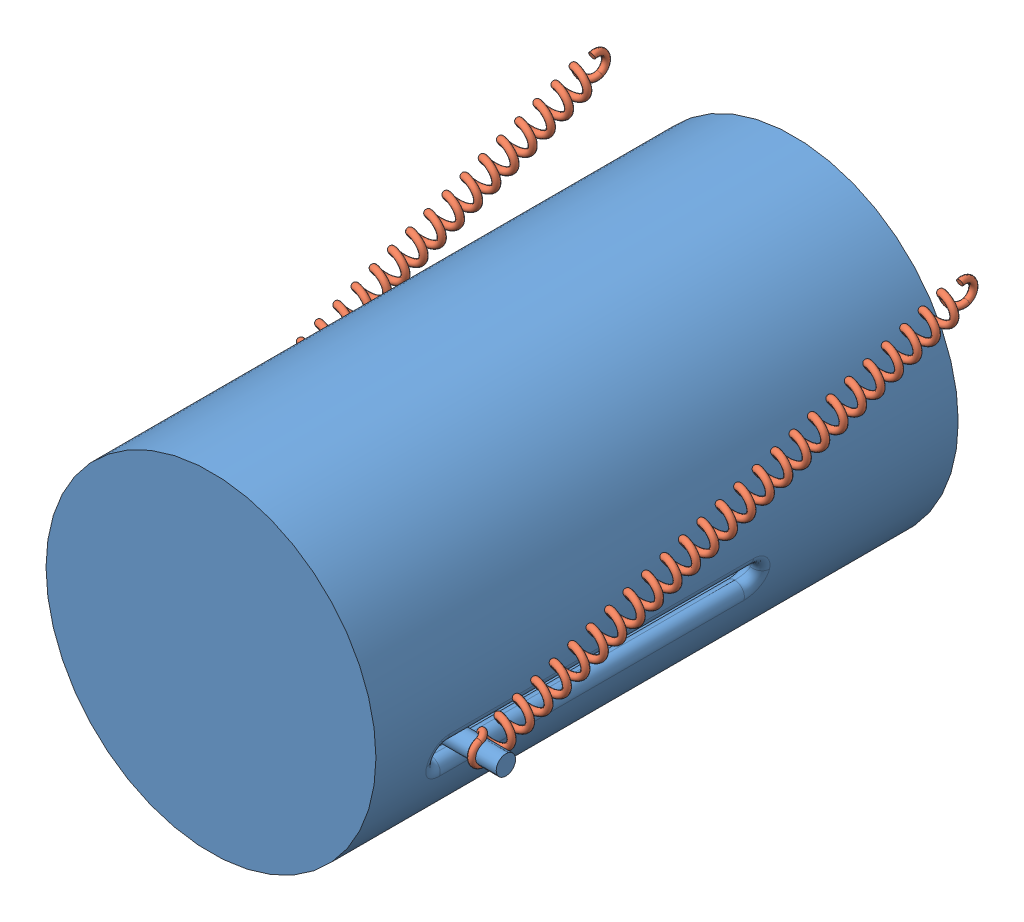
SolidWorks assembly assembly spring to cylinder, configuration Default. Lengths in mm.
Overall size (62.1 51 91.76).
3 component instances, 2 part files, 3 mates.
Components (placement in the parent):
- bottom part-1: bottom part [Default] at (17.6442 59.2949 24.1241) size (62 51 90)
- spring-1: spring [Default] at (-10.7255 80.6299 27.7939) x (0 -0.936629 -0.350322) z (-1 0 0) size (5.47 82.4 5.47)
- spring-2: spring [Default] at (44.9754 77.586 26.7279) x (0 -0.950546 -0.310585) z (-1 0 0) size (5.47 82.4 5.47)
Mates (geometry in assembly coordinates):
- Concentric1: concentric: cylinder of bottom part-1 through (-13.3558 53.7952 99.5397) axis (1 0 0) radius 1.5; circle of spring-1
- Concentric3: concentric: cylinder of bottom part-1 through (-13.3558 53.7952 99.5397) axis (1 0 0) radius 1.5; circle of spring-1
- Concentric5: concentric: cylinder of bottom part-1 through (-13.3558 53.7952 99.5397) axis (1 0 0) radius 1.5; circle of spring-2
